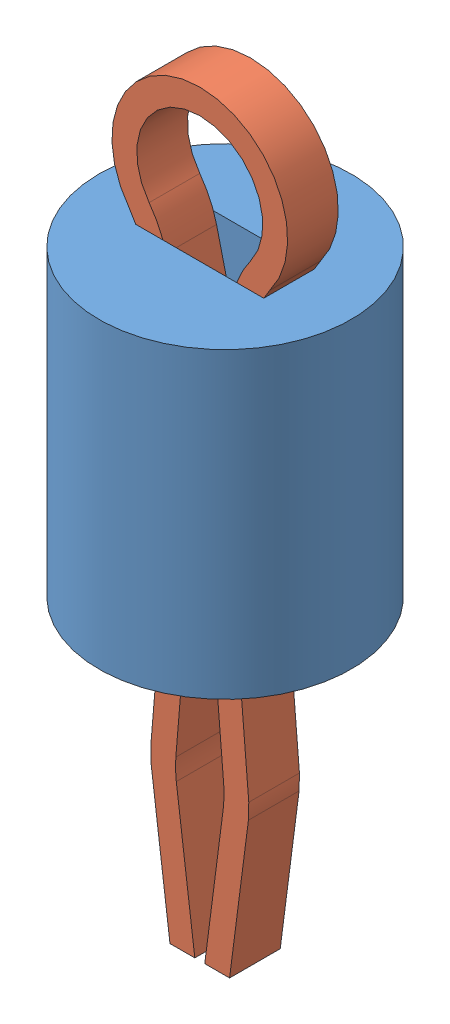
SolidWorks assembly Assem1, configuration Default. Lengths in mm.
Overall size (2.54 7.62 2.54).
2 component instances, 2 part files, 6 mates.
Components (placement in the parent):
- Spacer-black-1: Spacer-black [Default] x (-1 0 0) z (0 1 0) size (2.54 2.54 3.05)
- Contact-1: Contact [Default] x (1 0 0) z (0 1 0) size (1.77 0.51 7.62)
Mates (geometry in assembly coordinates):
- Coincident1: coincident aligned: plane of Spacer-black-1 through (0 0 0) normal (0 0 1)
- Coincident2: coincident anti-aligned: plane of Spacer-black-1 through (0 0 0) normal (-1 0 0)
- Coincident3: coincident anti-aligned: plane of Spacer-black-1 through (0 0 0) normal (0 -1 0)
- Coincident4: coincident anti-aligned: plane of Contact-1 through (0 0 0) normal (0 0 -1)
- Coincident5: coincident aligned: plane of Contact-1 through (0 0 0) normal (1 0 0)
- Distance1: distance = 3.05 mm aligned: plane of Spacer-black-1 through (0 0 0) normal (0 -1 0); plane of Contact-1 through (-0.175 -3.05 0) normal (0 -1 0)
